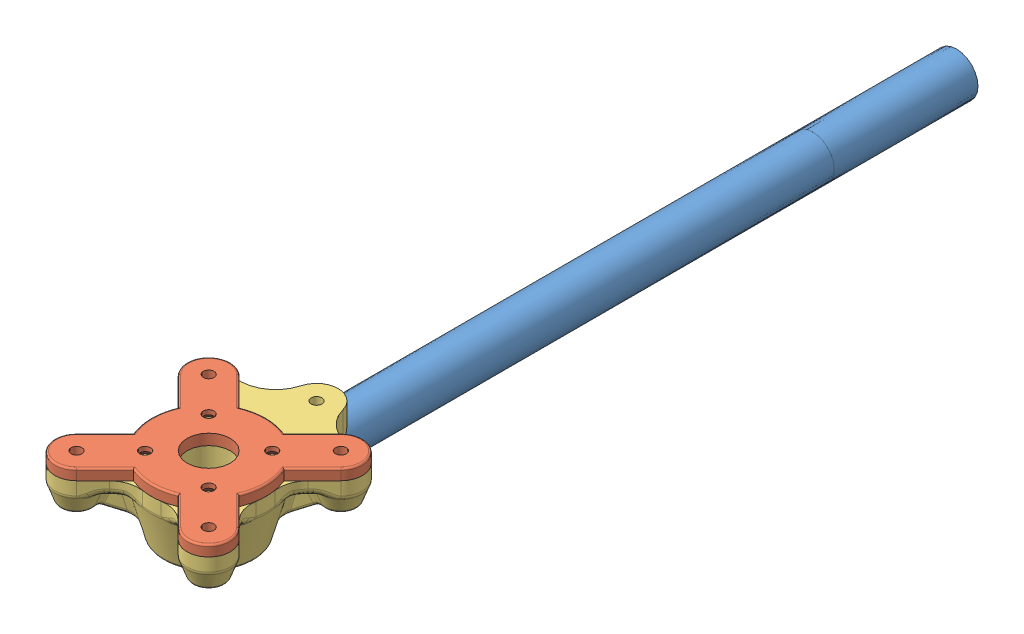
SolidWorks assembly mt7, configuration Varsayılan. Lengths in mm.
Overall size (90.51 21.4 253.25).
3 component instances, 3 part files, 6 mates.
Components (placement in the parent):
- boru-1: boru [Varsayılan] at (-1.0928 3.5507 0) size (12 12 200)
- motor-x-1: motor-x [Varsayılan] at (-1.0928 13.7507 208) x (0.707107 0 0.707107) z (-0.707107 0 0.707107) size (64 3 64)
- rocket-v2-1: rocket-v2 [full rib] at (-1.0928 9.7507 208) x (0.707107 0 -0.707107) z (0.707107 0 0.707107) size (64 18.4 64)
Mates (geometry in assembly coordinates):
- Coincident2: coincident anti-aligned: plane of boru-1 through (-1.0928 3.5507 200) normal (0 0 1); plane of rocket-v2-1 through (-1.0928 3.5507 200) normal (0 0 -1)
- Concentric10: concentric anti-aligned: cylinder of boru-1 through (-1.0928 3.5507 200) axis (0 0 -1) radius 6; cylinder of rocket-v2-1 through (-1.0928 3.5507 172) axis (0 0 1) radius 6.2
- Concentric11: concentric aligned: cylinder of boru-1 through (-1.0928 -2.4493 178) axis (0 1 0) radius 1.5; cylinder of rocket-v2-1 through (-1.0928 -20.2493 178) axis (0 1 0) radius 1.5
- Concentric12: concentric aligned: cylinder of motor-x-1 through (17.292 16.7507 189.6152) axis (0 -1 0) radius 1.5; cylinder of rocket-v2-1 through (17.292 13.7507 189.6152) axis (0 -1 0) radius 1.5
- Coincident3: coincident anti-aligned: plane of motor-x-1 through (17.292 13.7507 189.6152) normal (0 -1 0); plane of rocket-v2-1 through (-1.0928 13.7507 208) normal (0 1 0)
- Concentric13: concentric aligned: cylinder of motor-x-1 through (-19.4776 16.7507 189.6152) axis (0 -1 0) radius 1.5; cylinder of rocket-v2-1 through (-19.4776 13.7507 189.6152) axis (0 -1 0) radius 1.5
